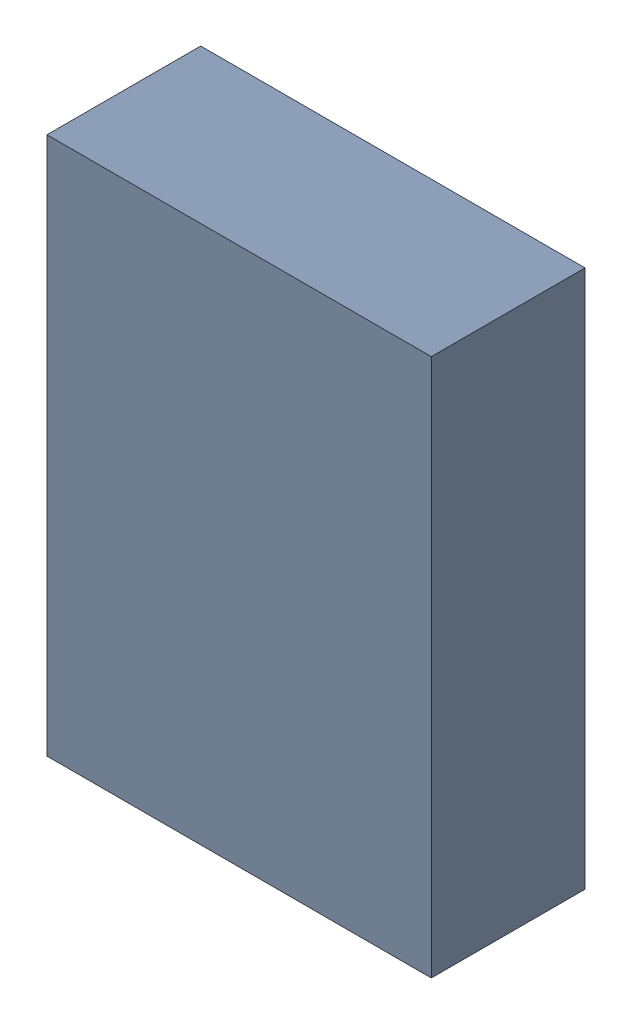
SolidWorks assembly U5Kanaloa_v2.0.0_GPIO_b, configuration Default. Lengths in mm.
Overall size (14 14 1.15).
2 component instances, 1 part files, 0 mates.
Components (placement in the parent):
- 352878416-1: 352878416 [Default] at (101.6 88.9 0.05) size (2.5 3.5 1)
  - Extruded-1: Extruded [Default] at origin size (2.5 3.5 1)
